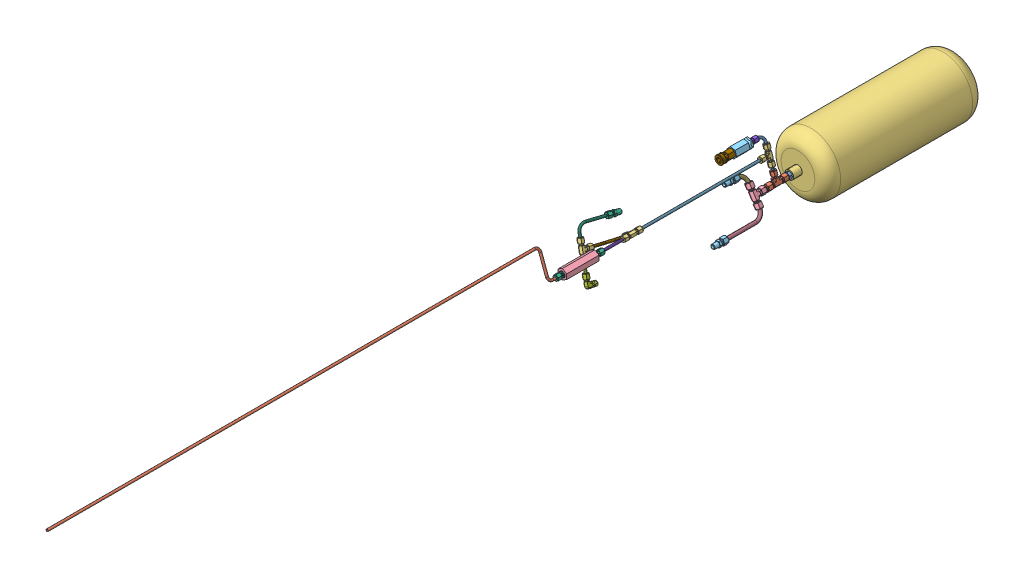
SolidWorks assembly HighPress_Assembly, configuration Default. Lengths in mm.
Overall size (202.89 228.78 2626.49).
28 component instances, 23 part files, 63 mates.
Components (placement in the parent):
- 6_F_Swage-10_M_NPT-1: 6_F_Swage-10_M_NPT [5182K153] at (15.3444 24.1934 48.3065) size (17.58 20.16 40.04)
- 6_M_Swage-4_M_Swage_Tee-1: 6_M_Swage-4_M_Swage_Tee [5182K364] at (15.3444 24.1934 92.2485) x (0.945071 0.326865 0) z (0 0 1) size (17.46 39.04 60.96)
- 4_M_Swage_Tee-1: 4_M_Swage_Tee [5182K434] at (3.3889 58.7603 61.7685) x (0.945071 0.326865 0) z (0.326865 -0.945071 0) size (14.29 35.17 53.85)
- 6_M_Swage_Tee-1: 6_M_Swage_Tee [5182K436] at (-1.2278 49.7745 126.7925) x (0.839275 0.543708 0) z (-0.543708 0.839275 0) size (17.46 40.56 60.96)
- 6_M_Swage-8_M_NPT-1: 6_M_Swage-8_M_NPT [5182K119] at (-12.6903 67.468 147.8745) x (0.051227 -0.998687 0) z (0 0 -1) size (17.46 20.16 39.88)
- 6_M_Swage-8_M_NPT-2: 6_M_Swage-8_M_NPT [5182K119] at (43.379 -19.0813 236.7745) x (-0.839275 -0.543708 0) z (0 0 -1) size (17.46 20.16 39.88)
- 4_M_Swage_Tee-2: 4_M_Swage_Tee [5182K434] at (-5.4116 84.2054 493.0605) x (-0.6165 0.787355 0) z (0 0 1) size (14.29 35.17 53.85)
- 4_M_Swage-8_M_NPT-2: 4_M_Swage-8_M_NPT [5182K111] at (-5.4116 84.2054 551.4805) x (-1 0 0) z (0 0 -1) size (14.29 16.5 37.85)
- 4_M_Swage-8_M_NPT-3: 4_M_Swage-8_M_NPT [5182K111] at (-5.4116 84.2054 691.0535) size (14.29 16.5 37.85)
- 4_M_Swage-8_M_NPT-4: 4_M_Swage-8_M_NPT [5182K111] at (-85.601 89.3547 460.9874) x (-0.628696 -0.77724 0.025279) z (-0.131826 0.138555 0.981542) size (14.29 16.5 37.85)
- 4_M_Swage-8_M_NPT_Elbow-1: 4_M_Swage-8_M_NPT_Elbow [5929K75] at (-54.5102 3.711 552.8153) x (0.910627 0.404626 0.083882) z (-0.3856 0.905029 -0.179543) size (14.48 32.03 34.26)
- 4_M_Swage_Tee-3: 4_M_Swage_Tee [5182K434] at (-84.2793 73.5811 538.9543) x (0.91554 0.399446 0.047219) z (-0.3856 0.905029 -0.179543) size (14.29 35.17 53.85)
- 4_M_Swage-6_M_NPT-1: 4_M_Swage-6_M_NPT [5182K807] at (-20.854 128.8543 82.0885) x (0.755609 -0.655023 0) z (0 0 -1) size (14.29 16.5 32.77)
- F_QD-8_F_NPT-1: F_QD-8_F_NPT [6543K33] at (-20.854 128.8543 156.0025) x (0 0 -1) z (0.189462 0.981888 0) size (38.1 26.13 24.65)
- 4_Thick_L1.5in-1: 4_Thick_L1.5in [Default] at (10.8611 37.156 61.7685) x (-0.008947 -0.003094 0.999955) z (-0.945029 -0.326851 -0.009467) size (6.35 38.1 6.35)
- 6_Thick_L1.5in-2: 6_Thick_L1.5in [Default] at (15.3444 24.1934 75.2305) x (1 0 0) z (0 -1 0) size (9.53 38.1 9.53)
- 6_Thick_D90_R.94in_L1.5x1.5in-3: 6_Thick_D90_R.94in_L1.5x1.5in [Default] at (-12.6903 67.468 126.7925) x (0 0 1) z (-0.839275 -0.543708 0) size (42.86 42.86 9.53)
- 6_Thick_D90_R.94in_L1.5x5in-1: 6_Thick_D90_R.94in_L1.5x5in [Default] at (43.379 -19.0813 126.7925) x (-0.543708 0.839275 0) z (-0.839275 -0.543708 0) size (42.86 131.76 9.53)
- 4_Thick_L15in-1: 4_Thick_L15in [Default] at (-5.4116 84.2054 454.4525) x (0.960639 -0.2778 0) z (0.2778 0.960639 0) size (6.35 381 6.35)
- 4_Thick_D90_R.75in_L3.21x3.53in-1: 4_Thick_D90_R.75in_L3.21x3.53in [Default] at (-93.0677 97.2025 516.5822) x (0.3856 -0.905029 0.179543) z (-0.9132 -0.402151 -0.065879) size (68.69 92.58 6.35)
- 4_Thick_L2.12in-2: 4_Thick_L2.12in [Default] at (-69.392 38.6397 545.8861) x (-0.56356 -0.385096 -0.730822) z (-0.730556 -0.180622 0.658531) size (6.35 53.83 6.35)
- 4_Thick_L3.5in-1: 4_Thick_L3.5in [Default] at (-5.4116 84.2054 566.7205) x (1 0 0) z (0 1 0) size (6.35 88.9 6.35)
- 4_Thick_D90_R.75in_L2.5x2.04in-2: 4_Thick_D90_R.75in_L2.5x2.04in [Default] at (-51.0523 48.4687 466.1365) x (-0.114452 0.146171 0.982616) z (0.605783 -0.773668 0.185648) size (66.67 55.08 6.35)
- 4_Thick_D90_R.75in_L1.4x1.4in-1: 4_Thick_D90_R.75in_L1.4x1.4in [Default] at (-20.854 128.8543 79.2962) x (0.326865 -0.945071 0) z (0.945071 0.326865 0) size (38.73 38.74 6.35)
- 4_HighPress_to_Pnematics-1: 4_HighPress_to_Pnematics [Default] at (-5.4116 84.2054 675.8135) x (0 0 1) z (0.347839 -0.937554 0) size (1483.36 6.35 88.54)
- COPV_D7in-1: COPV_D7in [Default] at (15.3444 24.1934 -234.9035) x (1 0 0) z (0 1 0) size (175.26 490.22 175.26)
- Inline_Regulator-1: Inline_Regulator [Default] at (-5.4116 84.2054 670.3525) x (0.866025 0.5 0) z (0 0 -1) size (29.33 25.4 95.25)
- HP_Check_Valve-1: HP_Check_Valve [6543K43] at (-20.854 128.8543 168.3652) x (0 0 1) z (0.326865 -0.945071 0) size (63.16 25.4 30.98)
Mates (geometry in assembly coordinates):
- Concentric1: concentric anti-aligned: cylinder of 6_F_Swage-10_M_NPT-1 through (15.3444 24.1934 30.7805) axis (0 0 -1) radius 4.7625; cylinder of COPV_D7in-1 through (15.3444 24.1934 -2.4935) axis (0 0 1) radius 7.9375
- Coincident2: coincident anti-aligned: plane of 6_F_Swage-10_M_NPT-1 through (15.3444 34.2753 22.9065) normal (0 0 -1); plane of COPV_D7in-1 through (15.3444 24.1934 22.9065) normal (0 0 1)
- Coincident3: coincident anti-aligned: plane of 6_F_Swage-10_M_NPT-1 through (15.3444 24.1934 48.3065) normal (0 0 1); plane of 6_M_Swage-4_M_Swage_Tee-1 through (16.9011 19.6925 48.3065) normal (0 0 -1)
- Concentric2: concentric aligned: cylinder of 6_F_Swage-10_M_NPT-1 through (15.3444 24.1934 30.7805) axis (0 0 -1) radius 4.7625; cylinder of 6_M_Swage-4_M_Swage_Tee-1 through (15.3444 24.1934 31.2885) axis (0 0 -1) radius 4.7625
- Coincident4: coincident anti-aligned: plane of 6_M_Swage-4_M_Swage_Tee-1 through (10.8611 37.156 59.3936) normal (-0.326865 0.945071 0); plane of 4_Thick_L1.5in-1 through (10.8611 37.156 61.7685) normal (0.326865 -0.945071 0)
- Concentric3: concentric aligned: cylinder of 6_M_Swage-4_M_Swage_Tee-1 through (15.3444 24.1934 61.7685) axis (0.326865 -0.945071 0) radius 3.175; cylinder of 4_Thick_L1.5in-1 through (-1.5925 73.1632 61.7685) axis (0.326865 -0.945071 0) radius 3.175
- Coincident5: coincident anti-aligned: plane of 4_Thick_L1.5in-1 through (-1.5925 73.1632 61.7685) normal (-0.326865 0.945071 0); plane of 4_M_Swage_Tee-1 through (-1.5925 73.1632 64.9435) normal (0.326865 -0.945071 0)
- Concentric4: concentric aligned: cylinder of 4_Thick_L1.5in-1 through (-1.5925 73.1632 61.7685) axis (0.326865 -0.945071 0) radius 3.175; cylinder of 4_M_Swage_Tee-1 through (3.3889 58.7603 61.7685) axis (0.326865 -0.945071 0) radius 3.175
- Parallel1: parallel aligned: plane of 6_M_Swage-4_M_Swage_Tee-1 through (9.3408 17.2679 61.7685) normal (-0.945071 -0.326865 0); plane of 4_M_Swage_Tee-1 through (-10.2144 78.665 70.9125) normal (-0.945071 -0.326865 0)
- Coincident7: coincident anti-aligned: plane of 6_M_Swage-4_M_Swage_Tee-1 through (13.7877 28.6943 75.2305) normal (0 0 1); plane of 6_Thick_L1.5in-2 through (15.3444 24.1934 75.2305) normal (0 0 -1)
- Concentric5: concentric anti-aligned: cylinder of 6_M_Swage-4_M_Swage_Tee-1 through (15.3444 24.1934 92.2485) axis (0 0 1) radius 4.7625; cylinder of 6_Thick_L1.5in-2 through (15.3444 24.1934 113.3305) axis (0 0 -1) radius 4.7625
- Coincident8: coincident anti-aligned: plane of 6_Thick_L1.5in-2 through (15.3444 24.1934 113.3305) normal (0 0 1); plane of 6_M_Swage_Tee-1 through (17.9338 20.1963 113.3305) normal (0 0 -1)
- Concentric6: concentric aligned: cylinder of 6_Thick_L1.5in-2 through (15.3444 24.1934 113.3305) axis (0 0 -1) radius 4.7625; cylinder of 6_M_Swage_Tee-1 through (15.3444 24.1934 96.3125) axis (0 0 -1) radius 4.7625
- Coincident10: coincident anti-aligned: plane of 6_M_Swage_Tee-1 through (8.025 35.4917 122.03) normal (-0.543708 0.839275 0); plane of 6_Thick_D90_R.94in_L1.5x1.5in-3 through (8.025 35.4917 126.7925) normal (0.543708 -0.839275 0)
- Concentric8: concentric aligned: cylinder of 6_M_Swage_Tee-1 through (-1.2278 49.7745 126.7925) axis (-0.543708 0.839275 0) radius 4.7625; cylinder of 6_Thick_D90_R.94in_L1.5x1.5in-3 through (8.025 35.4917 126.7925) axis (-0.543708 0.839275 0) radius 4.7625
- Perpendicular1: perpendicular: plane of 6_M_Swage_Tee-1 through (24.4978 24.6629 115.6165) normal (0.839275 0.543708 0); plane of 6_Thick_D90_R.94in_L1.5x1.5in-3 through (-12.6903 67.468 164.8925) normal (0 0 1)
- Coincident12: coincident anti-aligned: plane of 6_M_Swage_Tee-1 through (22.6638 12.8951 131.555) normal (0.543708 -0.839275 0); plane of 6_Thick_D90_R.94in_L1.5x5in-1 through (22.6638 12.8951 126.7925) normal (-0.543708 0.839275 0)
- Concentric9: concentric anti-aligned: cylinder of 6_M_Swage_Tee-1 through (31.9166 -1.3877 126.7925) axis (0.543708 -0.839275 0) radius 4.7625; cylinder of 6_Thick_D90_R.94in_L1.5x5in-1 through (30.432 0.9039 126.7925) axis (-0.543708 0.839275 0) radius 4.7625
- Perpendicular3: perpendicular: plane of 6_M_Swage_Tee-1 through (16.855 5.8029 131.8335) normal (-0.839275 -0.543708 0); plane of 6_Thick_D90_R.94in_L1.5x5in-1 through (43.379 -19.0813 253.7925) normal (0 0 1)
- Coincident15: coincident anti-aligned: plane of 6_M_Swage-8_M_NPT-1 through (-17.4465 67.2241 164.8925) normal (0 0 -1); plane of 6_Thick_D90_R.94in_L1.5x1.5in-3 through (-12.6903 67.468 164.8925) normal (0 0 1)
- Concentric10: concentric anti-aligned: cylinder of 6_M_Swage-8_M_NPT-1 through (-12.6903 67.468 147.8745) axis (0 0 -1) radius 4.7625; cylinder of 6_Thick_D90_R.94in_L1.5x1.5in-3 through (-12.6903 67.468 150.605) axis (0 0 1) radius 4.7625
- Parallel6: parallel aligned: plane of 6_M_Swage_Tee-1 through (6.191 23.7238 115.6165) normal (-0.839275 -0.543708 0); plane of 6_M_Swage-8_M_NPT-1 through (-17.2774 58.49 162.0985) normal (-0.839275 -0.543708 0)
- Coincident17: coincident anti-aligned: plane of 6_M_Swage-8_M_NPT-2 through (40.7896 -15.0843 253.7925) normal (0 0 -1); plane of 6_Thick_D90_R.94in_L1.5x5in-1 through (43.379 -19.0813 253.7925) normal (0 0 1)
- Concentric11: concentric aligned: cylinder of 6_M_Swage-8_M_NPT-2 through (43.379 -19.0813 236.7745) axis (0 0 -1) radius 4.7625; cylinder of 6_Thick_D90_R.94in_L1.5x5in-1 through (43.379 -19.0813 253.7925) axis (0 0 -1) radius 4.7625
- Parallel7: parallel aligned: plane of 6_M_Swage_Tee-1 through (6.191 23.7238 115.6165) normal (-0.839275 -0.543708 0); plane of 6_M_Swage-8_M_NPT-2 through (38.7919 -28.0593 250.9985) normal (-0.839275 -0.543708 0)
- Concentric12: concentric aligned: cylinder of 4_M_Swage_Tee-1 through (-5.4116 84.2054 88.6925) axis (0 0 1) radius 3.175; cylinder of 4_Thick_L15in-1 through (-5.4116 84.2054 73.4525) axis (0 0 1) radius 3.175
- Coincident18: coincident anti-aligned: plane of 4_M_Swage_Tee-1 through (-6.4494 87.206 73.4525) normal (0 0 1); plane of 4_Thick_L15in-1 through (-5.4116 84.2054 73.4525) normal (0 0 -1)
- Concentric13: concentric anti-aligned: cylinder of 4_M_Swage_Tee-2 through (-5.4116 84.2054 439.2125) axis (0 0 -1) radius 3.175; cylinder of 4_Thick_L15in-1 through (-5.4116 84.2054 73.4525) axis (0 0 1) radius 3.175
- Coincident19: coincident anti-aligned: plane of 4_M_Swage_Tee-2 through (-2.9117 86.1628 454.4525) normal (0 0 -1); plane of 4_Thick_L15in-1 through (-5.4116 84.2054 454.4525) normal (0 0 1)
- Concentric25: concentric aligned: cylinder of 4_M_Swage-8_M_NPT-2 through (-5.4116 84.2054 551.4805) axis (0 0 -1) radius 4.6228; cylinder of Inline_Regulator-1 through (-5.4116 84.2054 592.2475) axis (0 0 -1) radius 6.858
- Coincident32: coincident anti-aligned: plane of 4_M_Swage-8_M_NPT-2 through (-5.4116 84.2054 575.1025) normal (0 0 1); plane of Inline_Regulator-1 through (-5.4116 84.2054 575.1025) normal (0 0 -1)
- Parallel11: parallel aligned: plane of 6_F_Swage-10_M_NPT-1 through (6.6131 29.2344 22.9065) normal (-0.5 0.866025 0); plane of 4_M_Swage-8_M_NPT-2 through (-12.5553 88.3298 564.1805) normal (-0.5 0.866025 0)
- Parallel12: parallel aligned: plane of 4_M_Swage-8_M_NPT-2 through (-12.5553 88.3298 564.1805) normal (-0.5 0.866025 0); plane of Inline_Regulator-1 through (-18.1116 91.5377 575.1025) normal (-0.5 0.866025 0)
- Coincident40: coincident anti-aligned: plane of Inline_Regulator-1 through (-5.4116 84.2054 653.2075) normal (0 0 1); plane of 4_M_Swage-8_M_NPT-3 through (-5.4116 84.2054 653.2075) normal (0 0 -1)
- Concentric26: concentric anti-aligned: cylinder of Inline_Regulator-1 through (-5.4116 84.2054 653.2075) axis (0 0 1) radius 6.858; cone of 4_M_Swage-8_M_NPT-3 through (-5.4116 84.2054 653.2075) axis (0 0 -1)
- Parallel16: parallel aligned: plane of Inline_Regulator-1 through (-5.4116 98.8701 575.1025) normal (0.5 0.866025 0); plane of 4_M_Swage-8_M_NPT-3 through (1.7322 88.3298 678.3535) normal (0.5 0.866025 0)
- Coincident41: coincident anti-aligned: plane of 4_M_Swage-8_M_NPT_Elbow-1 through (-48.1619 -10.498 552.4395) normal (-0.3856 0.905029 -0.179543); plane of 4_Thick_L2.12in-2 through (-48.6336 -10.0816 555.5516) normal (0.3856 -0.905029 0.179543)
- Coincident42: coincident aligned: circle of 4_M_Swage-8_M_NPT_Elbow-1; cylinder of 4_Thick_L2.12in-2 through (-48.6336 -10.0816 555.5516) axis (-0.3856 0.905029 -0.179543) radius 3.175
- Coincident43: coincident anti-aligned: plane of 4_M_Swage_Tee-3 through (-69.7554 39.1038 549.0059) normal (0.3856 -0.905029 0.179543); plane of 4_Thick_L2.12in-2 through (-69.392 38.6397 545.8861) normal (-0.3856 0.905029 -0.179543)
- Concentric27: concentric anti-aligned: cylinder of 4_M_Swage_Tee-3 through (-63.5155 24.8471 548.6223) axis (0.3856 -0.905029 0.179543) radius 3.175; cylinder of 4_Thick_L2.12in-2 through (-48.6336 -10.0816 555.5516) axis (-0.3856 0.905029 -0.179543) radius 3.175
- Concentric28: concentric anti-aligned: cylinder of 4_M_Swage_Tee-3 through (-84.2793 73.5811 538.9543) axis (-0.3856 0.905029 -0.179543) radius 2.3749; cylinder of 4_Thick_D90_R.75in_L3.21x3.53in-1 through (-88.0326 82.3902 537.2067) axis (0.3856 -0.905029 0.179543) radius 3.175
- Coincident46: coincident anti-aligned: plane of 4_M_Swage-8_M_NPT-4 through (-81.1587 85.2944 446.6306) normal (-0.131826 0.138555 0.981542); plane of 4_Thick_D90_R.75in_L3.21x3.53in-1 through (-83.592 87.2431 446.0287) normal (0.131826 -0.138555 -0.981542)
- Concentric29: concentric aligned: cylinder of 4_M_Swage-8_M_NPT-4 through (-85.601 89.3547 460.9874) axis (-0.131826 0.138555 0.981542) radius 3.175; cylinder of 4_Thick_D90_R.75in_L3.21x3.53in-1 through (-83.592 87.2431 446.0287) axis (-0.131826 0.138555 0.981542) radius 3.175
- Coincident51: coincident anti-aligned: plane of 4_M_Swage_Tee-2 through (-7.9114 82.248 477.8205) normal (0 0 1); plane of 4_Thick_L3.5in-1 through (-5.4116 84.2054 477.8205) normal (0 0 -1)
- Concentric33: concentric aligned: cylinder of 4_M_Swage_Tee-2 through (-5.4116 84.2054 493.0605) axis (0 0 1) radius 3.175; cylinder of 4_Thick_L3.5in-1 through (-5.4116 84.2054 477.8205) axis (0 0 1) radius 3.175
- Coincident52: coincident anti-aligned: plane of 4_M_Swage-8_M_NPT-2 through (-5.4116 87.3804 566.7205) normal (0 0 -1); plane of 4_Thick_L3.5in-1 through (-5.4116 84.2054 566.7205) normal (0 0 1)
- Concentric34: concentric anti-aligned: cylinder of 4_M_Swage-8_M_NPT-2 through (-5.4116 84.2054 551.4805) axis (0 0 -1) radius 3.175; cylinder of 4_Thick_L3.5in-1 through (-5.4116 84.2054 477.8205) axis (0 0 1) radius 3.175
- Concentric35: concentric aligned: cylinder of 4_M_Swage_Tee-2 through (-26.6103 67.6067 466.1365) axis (-0.787355 -0.6165 0) radius 3.175; cylinder of 4_Thick_D90_R.75in_L2.5x2.04in-2 through (-23.9824 69.6644 466.1365) axis (-0.787355 -0.6165 0) radius 3.175
- Concentric37: concentric anti-aligned: cylinder of 4_M_Swage_Tee-3 through (-70.8159 45.2786 517.3323) axis (0.114452 -0.146171 -0.982616) radius 3.175; cylinder of 4_Thick_D90_R.75in_L2.5x2.04in-2 through (-67.0331 40.4474 484.8553) axis (-0.114452 0.146171 0.982616) radius 3.175
- Coincident53: coincident anti-aligned: plane of 4_M_Swage_Tee-1 through (-9.2307 95.2476 58.5935) normal (-0.326865 0.945071 0); plane of 4_Thick_D90_R.75in_L1.4x1.4in-1 through (-9.2307 95.2476 61.7685) normal (0.326865 -0.945071 0)
- Concentric38: concentric anti-aligned: cylinder of 4_M_Swage_Tee-1 through (-14.2121 109.6505 61.7685) axis (-0.326865 0.945071 0) radius 3.175; cylinder of 4_Thick_D90_R.75in_L1.4x1.4in-1 through (-14.6272 110.8507 61.7685) axis (0.326865 -0.945071 0) radius 3.175
- Parallel17: parallel anti-aligned: cylinder of 4_Thick_L15in-1 through (-5.4116 84.2054 73.4525) axis (0 0 1) radius 3.175; cylinder of 4_Thick_D90_R.75in_L1.4x1.4in-1 through (-20.854 128.8543 97.3285) axis (0 0 -1) radius 3.175
- Coincident54: coincident anti-aligned: plane of 4_Thick_D90_R.75in_L1.4x1.4in-1 through (-20.854 128.8543 97.3285) normal (0 0 1); plane of 4_M_Swage-6_M_NPT-1 through (-22.9337 126.4552 97.3285) normal (0 0 -1)
- Concentric40: concentric aligned: cylinder of 4_Thick_D90_R.75in_L1.4x1.4in-1 through (-20.854 128.8543 97.3285) axis (0 0 -1) radius 3.175; cylinder of 4_M_Swage-6_M_NPT-1 through (-20.854 128.8543 82.0885) axis (0 0 -1) radius 3.4163
- Parallel18: parallel aligned: plane of 4_M_Swage_Tee-1 through (-10.2144 78.665 70.9125) normal (-0.945071 -0.326865 0); plane of 4_M_Swage-6_M_NPT-1 through (-26.2572 122.6214 94.7885) normal (-0.945071 -0.326865 0)
- Coincident56: coincident anti-aligned: plane of 4_M_Swage-6_M_NPT-1 through (-20.854 128.8543 105.2025) normal (0 0 1); plane of HP_Check_Valve-1 through (-20.854 128.8543 105.2025) normal (0 0 -1)
- Concentric41: concentric anti-aligned: cone of 4_M_Swage-6_M_NPT-1 through (-20.854 128.8543 114.8545) axis (0 0 1); cylinder of HP_Check_Valve-1 through (-20.854 128.8543 192.2412) axis (0 0 -1) radius 3.0956
- Parallel19: parallel aligned: plane of 4_M_Swage-6_M_NPT-1 through (-26.2572 122.6214 94.7885) normal (-0.945071 -0.326865 0); plane of HP_Check_Valve-1 through (-30.4597 117.7735 105.2025) normal (-0.945071 -0.326865 0)
- Coincident59: coincident anti-aligned: plane of HP_Check_Valve-1 through (-20.854 128.8543 156.0025) normal (0 0 1); plane of F_QD-8_F_NPT-1 through (-20.854 128.8543 156.0025) normal (0 0 -1)
- Concentric43: concentric anti-aligned: cylinder of HP_Check_Valve-1 through (-20.854 128.8543 192.2412) axis (0 0 -1) radius 3.0956; cylinder of F_QD-8_F_NPT-1 through (-20.854 128.8543 183.244) axis (0 0 1) radius 6.2508
- Parallel20: parallel aligned: plane of HP_Check_Valve-1 through (-25.6474 142.7135 105.2025) normal (0.189462 0.981888 0); plane of F_QD-8_F_NPT-1 through (-24.7366 140.0802 165.5275) normal (0.189462 0.981888 0)
- Coincident63: coincident anti-aligned: plane of 4_M_Swage-8_M_NPT-3 through (-5.4116 87.3804 675.8135) normal (0 0 1); plane of 4_HighPress_to_Pnematics-1 through (-5.4116 84.2054 675.8135) normal (0 0 -1)
- Concentric46: concentric aligned: cylinder of 4_M_Swage-8_M_NPT-3 through (-5.4116 84.2054 691.0535) axis (0 0 1) radius 3.175; cylinder of 4_HighPress_to_Pnematics-1 through (-5.4116 84.2054 675.8135) axis (0 0 1) radius 3.175
